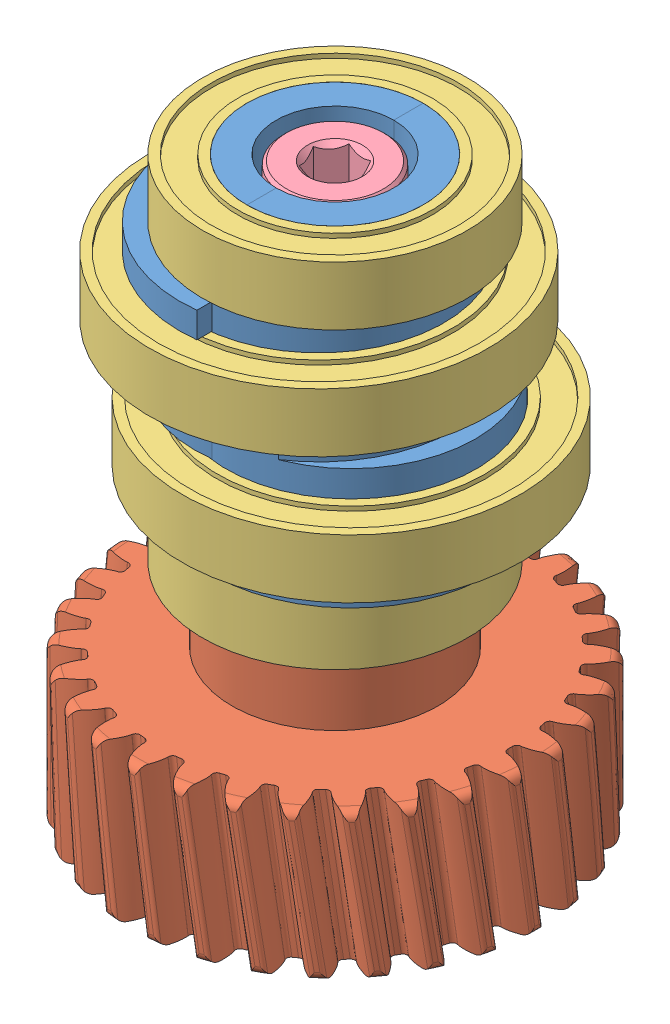
SolidWorks assembly Wobbler Assem, configuration Default. Lengths in mm.
Overall size (30.56 44.78 28.88).
8 component instances, 5 part files, 19 mates.
Components (placement in the parent):
- Eccentric Shaft - FDM-1: Eccentric Shaft - FDM [Default] x (-1 0 0) z (0 0 -1) size (21.1 22.5 18.9)
- Spur Gear-1: Spur Gear [Large] at (0 -9 0) x (1 0 0) z (0 1 0) size (27.81 27.81 18.06)
- bearing-4: bearing [6701] at (0 -2 0) x (0 1 0) z (-0.777842 0 -0.62846) size (4 18 18)
- bearing-3: bearing [6701] at (0 18 0) x (0 1 0) z (-0.917921 0 0.396763) size (4 18 18)
- bearing-2: bearing [6703] at (-1.1 11.75 0) x (0 1 0) z (0.239406 0 0.97092) size (4 23 23)
- bearing-1: bearing [6703] at (1.1 4.25 0) x (0 1 0) z (0.953192 0 0.302367) size (4 23 23)
- DIN912-M4x40-1: DIN912-M4x40 [91290A184] at (0 -2.4 0) x (0.137096 0 -0.990558) z (0 1 0) size (7 7 44.43)
- DIN985-M4-Locknut-1: DIN985-M4-Locknut [90576A103] at (0 -15.5 0) x (0.866025 0 0.5) z (0 -1 0) size (7 8.08 5.09)
Mates (geometry in assembly coordinates):
- Concentric46: concentric anti-aligned: cylinder of Eccentric Shaft - FDM-1 through (1.1 0 0) axis (0 -1 0) radius 8.45; cylinder of bearing-1 through (1.1 10.7312 0) axis (0 1 0) radius 8.5
- Coincident1: coincident anti-aligned: plane of Eccentric Shaft - FDM-1 through (0 9.75 0) normal (0 1 0); plane of bearing-2 through (-9.3528 9.75 2.035) normal (0 -1 0)
- Coincident2: coincident anti-aligned: plane of Eccentric Shaft - FDM-1 through (0 2.25 0) normal (0 1 0); plane of bearing-1 through (-1.4701 2.25 8.1021) normal (0 -1 0)
- Concentric48: concentric anti-aligned: cylinder of Eccentric Shaft - FDM-1 through (0 0 0) axis (0 -1 0) radius 6; cylinder of bearing-3 through (0 24.4812 0) axis (0 1 0) radius 6
- Coincident3: coincident anti-aligned: plane of Eccentric Shaft - FDM-1 through (7 16 0) normal (0 1 0); plane of bearing-3 through (-2.3806 16 -5.5075) normal (0 -1 0)
- Concentric49: concentric aligned: cylinder of Eccentric Shaft - FDM-1 through (0 0 0) axis (0 -1 0) radius 7; cylinder of Spur Gear-1 through (0 -9 0) axis (0 -1 0) radius 6
- Concentric50: concentric aligned: circle of Spur Gear-1; cylinder of bearing-4 through (0 4.4812 0) axis (0 1 0) radius 6
- Coincident5: coincident anti-aligned: plane of Spur Gear-1 through (0 -4 -6) normal (0 1 0); plane of bearing-4 through (3.7708 -4 -4.6671) normal (0 -1 0)
- Coincident7: coincident anti-aligned: plane of Eccentric Shaft - FDM-1 through (0 0 0) normal (0 0 -1)
- Coincident8: coincident aligned: plane of Eccentric Shaft - FDM-1 through (0 0 0) normal (0 1 0)
- Coincident9: coincident anti-aligned: plane of Eccentric Shaft - FDM-1 through (0 0 0) normal (-1 0 0)
- Coincident11: coincident anti-aligned: plane of Spur Gear-1 through (0 -13 0) normal (0 -1 0); plane of DIN985-M4-Locknut-1 through (0 -13 0) normal (0 1 0)
- Concentric52: concentric aligned: circle of DIN912-M4x40-1; circle of DIN985-M4-Locknut-1
- Parallel1: parallel anti-aligned: plane of Spur Gear-1 through (2.0785 -13 -3.6) normal (-0.866025 0 0.5); plane of DIN985-M4-Locknut-1 through (2.0207 -18 -3.5) normal (0.866025 0 -0.5)
- Concentric53: concentric anti-aligned: cylinder of Eccentric Shaft - FDM-1 through (0 20 0) axis (0 1 0) radius 4; cylinder of DIN912-M4x40-1 through (0 -24.4 0) axis (0 -1 0) radius 3.5
- Coincident13: coincident anti-aligned: plane of Eccentric Shaft - FDM-1 through (-2.15 15.6 0) normal (0 1 0); plane of DIN912-M4x40-1 through (-3.2688 15.6 -0.4524) normal (0 -1 0)
- Concentric54: concentric anti-aligned: cylinder of Eccentric Shaft - FDM-1 through (-1.1 0 0) axis (0 -1 0) radius 8.45; cylinder of bearing-2 through (-1.1 18.2312 0) axis (0 1 0) radius 8.5
- Coincident14: coincident anti-aligned: plane of Eccentric Shaft - FDM-1 through (6 0 0) normal (0 -1 0); plane of bearing-4 through (3.7708 0 -4.6671) normal (0 1 0)
- Parallel2: parallel aligned: line of Eccentric Shaft - FDM-1 through (-5.9925 -2.5 -0.3) axis (1 0 0); line of Spur Gear-1 through (3.85 -6 -3) axis (0 1 0)
